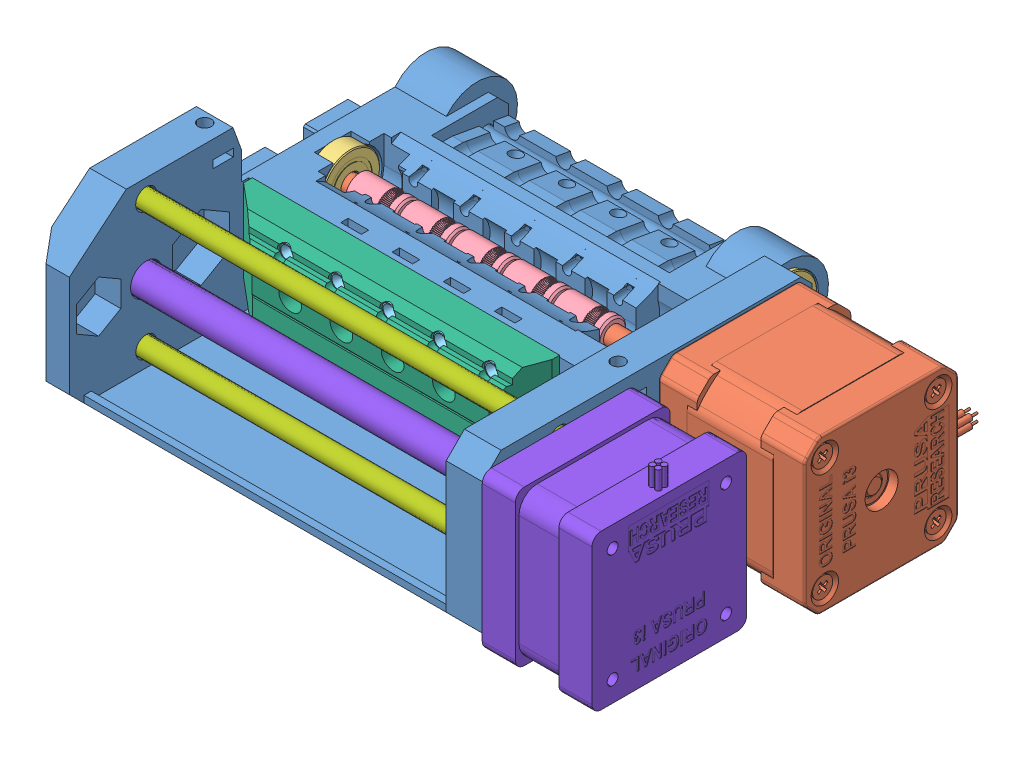
SolidWorks assembly MMU2 Pulley Body Assembly, configuration Default. Lengths in mm.
Overall size (163 48.15 110.15).
19 component instances, 8 part files, 44 mates.
Components (placement in the parent):
- mmu2-pulley-body(M1)-1: mmu2-pulley-body(M1) [Default] at (5.8785 74.1609 77.9167) x (1 0 0) z (0 1 0) size (123 110 46)
- Pulley Motor-1: Pulley Motor [NEMA 17 Stepper] at (141.8785 73.6609 77.9167) x (0 -1 0) z (0 0 -1) size (42.3 150 51.35)
- 625 Bearing-1: 625 Bearing [6153K15] at (-5.6215 73.6609 77.9167) x (0 -0.100672 -0.99492) z (1 0 0) size (16 16 5)
- Extruder Pulley-1: Extruder Pulley [Default] at (106.1795 -192.3915 231.3649) x (0 0.91085 0.412738) z (-1 0 0) size (9.1 8.2 13)
- Extruder Pulley-9: Extruder Pulley [Default] at (78.1795 -192.3915 231.3649) x (0 0.91085 0.412738) z (-1 0 0) size (9.1 8.2 13)
- Extruder Pulley-10: Extruder Pulley [Default] at (64.1795 -192.3915 231.3649) x (0 0.91085 0.412738) z (-1 0 0) size (9.1 8.2 13)
- Extruder Pulley-11: Extruder Pulley [Default] at (92.1795 -192.3915 231.3649) x (0 0.91085 0.412738) z (-1 0 0) size (9.1 8.2 13)
- Extruder Pulley-12: Extruder Pulley [Default] at (50.1785 -192.3915 231.3649) x (0 0.91085 0.412738) z (-1 0 0) size (9.1 8.2 13)
- PTFE 4x2x19-1: PTFE 4x2x19 [Default] at (8.8785 78.1609 107.4167) x (1 0 0) z (0 1 0) size (4 19 4)
- PTFE 4x2x19-2: PTFE 4x2x19 [Default] at (22.8785 78.1609 107.4167) x (0.418318 0.908301 0) z (-0.908301 0.418318 0) size (4 19 4)
- PTFE 4x2x19-3: PTFE 4x2x19 [Default] at (36.8785 78.1609 107.4167) x (1 0 0) z (0 1 0) size (4 19 4)
- PTFE 4x2x19-4: PTFE 4x2x19 [Default] at (50.8785 78.1609 107.4167) x (1 0 0) z (0 1 0) size (4 19 4)
- PTFE 4x2x19-5: PTFE 4x2x19 [Default] at (64.8785 78.1609 107.4167) x (1 0 0) z (0 1 0) size (4 19 4)
- mmu2-front-PTFE-holder(M1)-1: mmu2-front-PTFE-holder(M1) [Default] at (5.8785 74.1609 82.9167) x (1 0 0) z (0 1 0) size (84 15 22.5)
- Smooth Rod 5x120sh-1: Smooth Rod 5x120sh [Default] at (41.8785 55.1609 125.9167) x (0 0 -1) z (1 0 0) size (5 5 120)
- Smooth Rod 5x120sh-2: Smooth Rod 5x120sh [Default] at (41.8785 90.1609 125.9167) x (0 0.926511 -0.376267) z (1 0 0) size (5 5 120)
- Selector Motor-1: Selector Motor [Default] at (116.8785 71.1609 125.9167) x (0 1 0) z (-1 0 0) size (47.3 42.3 150)
- 625 Bearing-2: 625 Bearing [6153K15] at (-10.1215 74.1609 47.9167) x (0 0 -1) z (1 0 0) size (16 16 5)
- 625 Bearing-3: 625 Bearing [6153K15] at (83.8785 74.1609 47.9167) x (0 -0.091081 -0.995843) z (1 0 0) size (16 16 5)
Mates (geometry in assembly coordinates):
- Coincident1: coincident anti-aligned: plane of mmu2-pulley-body(M1)-1 through (101.8785 49.1609 142.9167) normal (1 0 0); plane of Pulley Motor-1 through (101.8785 73.6609 77.9167) normal (-1 0 0)
- Concentric1: concentric aligned: cylinder of mmu2-pulley-body(M1)-1 through (98.8785 73.6609 77.9167) axis (1 0 0) radius 11.5; cylinder of Pulley Motor-1 through (99.8785 73.6609 77.9167) axis (1 0 0) radius 11
- Concentric2: concentric aligned: cylinder of Pulley Motor-1 through (79.8785 73.6609 77.9167) axis (1 0 0) radius 2.5; cylinder of 625 Bearing-1 through (-3.1215 73.6609 77.9167) axis (1 0 0) radius 2.5
- Coincident3: coincident anti-aligned: plane of mmu2-pulley-body(M1)-1 through (-8.1215 77.1609 82.9167) normal (1 0 0); plane of 625 Bearing-1 through (-8.1215 81.3715 77.1365) normal (-1 0 0)
- Concentric3: concentric aligned: cylinder of mmu2-pulley-body(M1)-1 through (96.8785 89.1609 93.4167) axis (1 0 0) radius 1.65; cylinder of Pulley Motor-1 through (101.8785 89.1609 93.4167) axis (1 0 0) radius 1.25
- Concentric4: concentric aligned: cylinder of Extruder Pulley-1 through (54.7295 73.6609 77.9167) axis (1 0 0) radius 2.5; cylinder of Extruder Pulley-10 through (12.7295 73.6609 77.9167) axis (1 0 0) radius 2.5
- Concentric5: concentric aligned: cylinder of Extruder Pulley-1 through (54.7295 73.6609 77.9167) axis (1 0 0) radius 2.5; cylinder of Extruder Pulley-12 through (-1.2715 73.6609 77.9167) axis (1 0 0) radius 2.5
- Concentric6: concentric aligned: cylinder of Extruder Pulley-11 through (40.7295 73.6609 77.9167) axis (1 0 0) radius 2.5; cylinder of Extruder Pulley-12 through (-1.2715 73.6609 77.9167) axis (1 0 0) radius 2.5
- Concentric7: concentric aligned: cylinder of Extruder Pulley-9 through (26.7295 73.6609 77.9167) axis (1 0 0) radius 2.5; cylinder of Extruder Pulley-12 through (-1.2715 73.6609 77.9167) axis (1 0 0) radius 2.5
- Concentric8: concentric aligned: cylinder of Pulley Motor-1 through (79.8785 73.6609 77.9167) axis (1 0 0) radius 2.5; cylinder of Extruder Pulley-10 through (12.7295 73.6609 77.9167) axis (1 0 0) radius 2.5
- Coincident4: coincident aligned: plane of mmu2-pulley-body(M1)-1 through (64.8795 74.1609 77.9167) normal (1 0 0); plane of Extruder Pulley-1 through (64.8795 -192.3915 231.3649) normal (1 0 0)
- Coincident6: coincident aligned: plane of mmu2-pulley-body(M1)-1 through (50.8795 74.1609 77.9167) normal (1 0 0); plane of Extruder Pulley-11 through (50.8795 -192.3915 231.3649) normal (1 0 0)
- Coincident7: coincident aligned: plane of mmu2-pulley-body(M1)-1 through (36.8795 74.1609 77.9167) normal (1 0 0); plane of Extruder Pulley-9 through (36.8795 -192.3915 231.3649) normal (1 0 0)
- Coincident8: coincident aligned: plane of mmu2-pulley-body(M1)-1 through (22.8795 74.1609 77.9167) normal (1 0 0); plane of Extruder Pulley-10 through (22.8795 -192.3915 231.3649) normal (1 0 0)
- Coincident9: coincident aligned: plane of mmu2-pulley-body(M1)-1 through (8.8785 74.1609 77.9167) normal (1 0 0); plane of Extruder Pulley-12 through (8.8785 -192.3915 231.3649) normal (1 0 0)
- Parallel1: parallel aligned: plane of Pulley Motor-1 through (94.8785 71.2201 78.4575) normal (0 -0.91085 -0.412738); plane of Extruder Pulley-1 through (64.8795 69.1067 75.853) normal (0 -0.91085 -0.412738)
- Parallel2: parallel aligned: plane of Pulley Motor-1 through (94.8785 71.2201 78.4575) normal (0 -0.91085 -0.412738); plane of Extruder Pulley-11 through (50.8795 69.1067 75.853) normal (0 -0.91085 -0.412738)
- Parallel3: parallel aligned: plane of Pulley Motor-1 through (94.8785 71.2201 78.4575) normal (0 -0.91085 -0.412738); plane of Extruder Pulley-9 through (36.8795 69.1067 75.853) normal (0 -0.91085 -0.412738)
- Parallel4: parallel aligned: plane of Pulley Motor-1 through (94.8785 71.2201 78.4575) normal (0 -0.91085 -0.412738); plane of Extruder Pulley-10 through (22.8795 69.1067 75.853) normal (0 -0.91085 -0.412738)
- Parallel5: parallel aligned: plane of Pulley Motor-1 through (94.8785 71.2201 78.4575) normal (0 -0.91085 -0.412738); plane of Extruder Pulley-12 through (8.8785 69.1067 75.853) normal (0 -0.91085 -0.412738)
- Concentric9: concentric anti-aligned: cone of mmu2-pulley-body(M1)-1 through (8.8785 78.1609 97.9167) axis (0 0 -1); cylinder of PTFE 4x2x19-1 through (8.8785 78.1609 88.4167) axis (0 0 1) radius 2
- Concentric10: concentric anti-aligned: cone of mmu2-pulley-body(M1)-1 through (22.8785 78.1609 97.9167) axis (0 0 -1); cylinder of PTFE 4x2x19-2 through (22.8785 78.1609 88.4167) axis (0 0 1) radius 2
- Concentric11: concentric anti-aligned: cone of mmu2-pulley-body(M1)-1 through (36.8785 78.1609 97.9167) axis (0 0 -1); cylinder of PTFE 4x2x19-3 through (36.8785 78.1609 88.4167) axis (0 0 1) radius 2
- Concentric12: concentric anti-aligned: cone of mmu2-pulley-body(M1)-1 through (50.8785 78.1609 97.9167) axis (0 0 -1); cylinder of PTFE 4x2x19-4 through (50.8785 78.1609 88.4167) axis (0 0 1) radius 2
- Concentric13: concentric anti-aligned: cone of mmu2-pulley-body(M1)-1 through (64.8785 78.1609 97.9167) axis (0 0 -1); cylinder of PTFE 4x2x19-5 through (64.8785 78.1609 88.4167) axis (0 0 1) radius 2
- Coincident10: coincident aligned: plane of PTFE 4x2x19-1 through (8.8785 78.1609 88.4167) normal (0 0 -1); plane of PTFE 4x2x19-2 through (22.8785 78.1609 88.4167) normal (0 0 -1)
- Coincident11: coincident aligned: plane of PTFE 4x2x19-1 through (8.8785 78.1609 88.4167) normal (0 0 -1); plane of PTFE 4x2x19-3 through (36.8785 78.1609 88.4167) normal (0 0 -1)
- Coincident12: coincident aligned: plane of PTFE 4x2x19-1 through (8.8785 78.1609 88.4167) normal (0 0 -1); plane of PTFE 4x2x19-4 through (50.8785 78.1609 88.4167) normal (0 0 -1)
- Coincident13: coincident aligned: plane of PTFE 4x2x19-1 through (8.8785 78.1609 88.4167) normal (0 0 -1); plane of PTFE 4x2x19-5 through (64.8785 78.1609 88.4167) normal (0 0 -1)
- Coincident14: coincident anti-aligned: plane of mmu2-pulley-body(M1)-1 through (8.8785 78.1609 88.4167) normal (0 0 1); plane of PTFE 4x2x19-1 through (8.8785 78.1609 88.4167) normal (0 0 -1)
- Concentric14: concentric aligned: cylinder of PTFE 4x2x19-1 through (8.8785 78.1609 88.4167) axis (0 0 1) radius 2; cone of mmu2-front-PTFE-holder(M1)-1 through (8.8785 78.1609 97.9167) axis (0 0 1)
- Concentric15: concentric aligned: cylinder of PTFE 4x2x19-5 through (64.8785 78.1609 88.4167) axis (0 0 1) radius 2; cone of mmu2-front-PTFE-holder(M1)-1 through (64.8785 78.1609 97.9167) axis (0 0 1)
- Coincident15: coincident anti-aligned: plane of mmu2-pulley-body(M1)-1 through (-12.6215 50.1609 97.9167) normal (0 0 1); plane of mmu2-front-PTFE-holder(M1)-1 through (-10.1215 59.1609 97.9167) normal (0 0 -1)
- Concentric16: concentric aligned: cylinder of mmu2-pulley-body(M1)-1 through (96.8785 86.6609 141.4167) axis (1 0 0) radius 1.65; circle of Selector Motor-1
- Concentric17: concentric anti-aligned: cylinder of mmu2-pulley-body(M1)-1 through (96.8785 86.6609 110.4167) axis (1 0 0) radius 1.65; cylinder of Selector Motor-1 through (101.8785 86.6609 110.4167) axis (-1 0 0) radius 1.5
- Coincident16: coincident anti-aligned: plane of mmu2-pulley-body(M1)-1 through (101.8785 49.1609 142.9167) normal (1 0 0); plane of Selector Motor-1 through (101.8785 71.1609 125.9167) normal (-1 0 0)
- Coincident17: coincident aligned: plane of Smooth Rod 5x120sh-1 through (101.8785 55.1609 125.9167) normal (1 0 0); plane of Smooth Rod 5x120sh-2 through (101.8785 90.1609 125.9167) normal (1 0 0)
- Concentric19: concentric anti-aligned: cylinder of mmu2-pulley-body(M1)-1 through (-20.1215 90.1609 125.9167) axis (1 0 0) radius 2.7; cylinder of Smooth Rod 5x120sh-2 through (101.8785 90.1609 125.9167) axis (-1 0 0) radius 2.5
- Concentric20: concentric anti-aligned: cylinder of mmu2-pulley-body(M1)-1 through (-20.1215 55.1609 125.9167) axis (1 0 0) radius 2.6; cylinder of Smooth Rod 5x120sh-1 through (101.8785 55.1609 125.9167) axis (-1 0 0) radius 2.5
- Coincident18: coincident anti-aligned: plane of Smooth Rod 5x120sh-2 through (101.8785 90.1609 125.9167) normal (1 0 0); plane of Selector Motor-1 through (101.8785 71.1609 125.9167) normal (-1 0 0)
- Concentric22: concentric aligned: cylinder of mmu2-pulley-body(M1)-1 through (-9.1215 74.1609 47.9167) axis (1 0 0) radius 2.8; cylinder of 625 Bearing-2 through (-7.6215 74.1609 47.9167) axis (1 0 0) radius 2.5
- Coincident19: coincident aligned: plane of mmu2-pulley-body(M1)-1 through (-12.6215 29.1609 56.9167) normal (-1 0 0); plane of 625 Bearing-2 through (-12.6215 81.9109 47.9167) normal (-1 0 0)
- Concentric23: concentric aligned: cylinder of mmu2-pulley-body(M1)-1 through (77.3785 74.1609 47.9167) axis (1 0 0) radius 2.8; cylinder of 625 Bearing-3 through (86.3785 74.1609 47.9167) axis (1 0 0) radius 2.5
- Coincident20: coincident aligned: plane of mmu2-pulley-body(M1)-1 through (86.3785 29.1609 56.9167) normal (1 0 0); plane of 625 Bearing-3 through (86.3785 81.8787 47.2108) normal (1 0 0)
